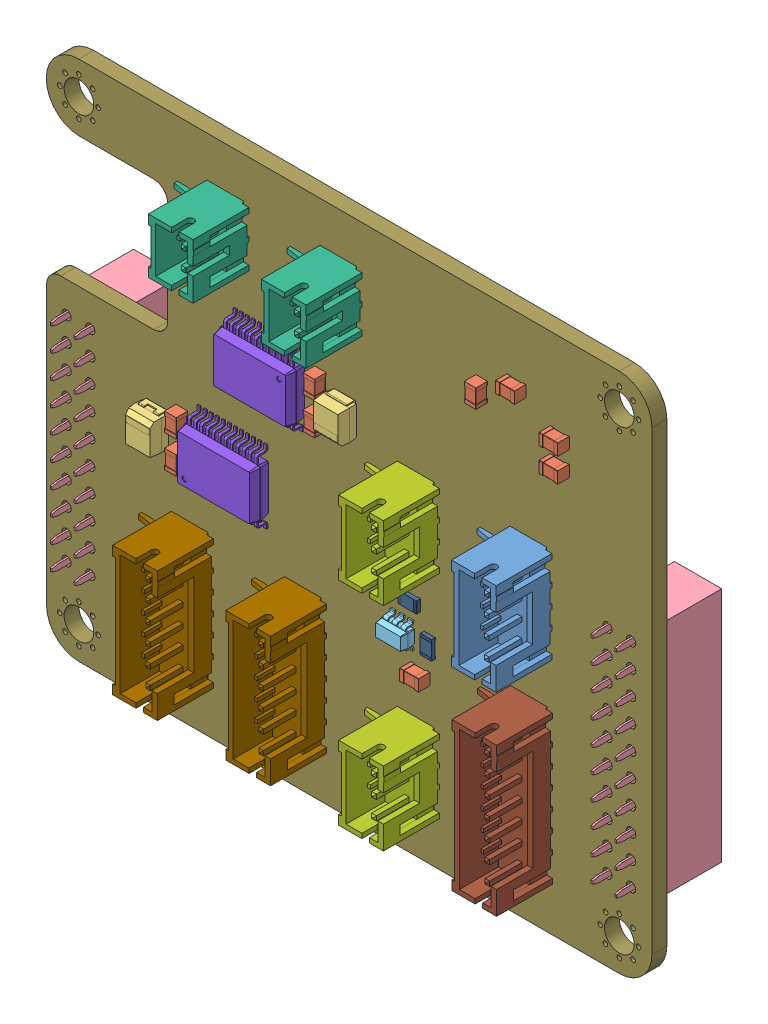
SolidWorks assembly seebum_peripherals, configuration Valor predeterminado. Lengths in mm.
Overall size (65 56 14.75).
54 component instances, 12 part files, 0 mates.
Components (placement in the parent):
- seebum_peripherals.step-1: seebum_peripherals.step [Valor predeterminado] at origin size (65 56 14.75)
  - JST_PH_S4B-PH-K_1x04_P2.00mm_Horizontal.step-1: JST_PH_S4B-PH-K_1x04_P2.00mm_Horizontal.step [Valor predeterminado] at (158.05 -87.4 1.65) x (0 -1 0) z (1 0 0) size (9.9 7.6 8.25)
    - JST_S4B_PH_K.step-1: JST_S4B_PH_K.step [Valor predeterminado] at origin size (9.9 7.6 8.25)
  - C_0805_2012Metric.step-1: C_0805_2012Metric.step [Valor predeterminado] at (122.875 -93 1.65) x (0 1 0) z (0 0 1) size (2 1.25 1.25)
    - C_0805_2012Metric-0.step-1: C_0805_2012Metric-0.step [Valor predeterminado] at origin size (2 1.25 1.25)
  - C_0805_2012Metric.step-2: C_0805_2012Metric.step [Valor predeterminado] at (158.8 -72 1.65) x (-1 0 0) z (0 0 1) size (2 1.25 1.25)
    - C_0805_2012Metric-0.step-1: C_0805_2012Metric-0.step [Valor predeterminado] at origin size (2 1.25 1.25)
  - CP_EIA-3528-21_Kemet-B.step-1: CP_EIA-3528-21_Kemet-B.step [Valor predeterminado] at (140.3917 -83.7275 1.65) x (0 1 0) z (0 0 1) size (3.5 2.8 2.1)
    - CP_EIA_3528_21_Kemet_B.step-1: CP_EIA_3528_21_Kemet_B.step [Valor predeterminado] at origin size (3.5 2.8 2.1)
  - PinSocket_2x10_P2.54mm_Vertical.step-1: PinSocket_2x10_P2.54mm_Vertical.step [Valor predeterminado] at (110.455 -89.64 0.15) x (-1 0 0) z (0 0 -1) size (5.08 25.4 10.1)
    - PinSocket_2x10_P254mm_Vertical.step-1: PinSocket_2x10_P254mm_Vertical.step [Valor predeterminado] at origin size (5.08 25.4 10.1)
  - SOT-23-5.step-1: SOT-23-5.step [Valor predeterminado] at (146.5625 -100.7 1.65) x (0 -1 0) z (0 0 1) size (2.8 2.9 1.55)
    - SOT_23_5.step-1: SOT_23_5.step [Valor predeterminado] at origin size (2.8 2.9 1.55)
  - CP_EIA-3528-21_Kemet-B.step-2: CP_EIA-3528-21_Kemet-B.step [Valor predeterminado] at (120.225 -94.7225 1.65) x (0 -1 0) z (0 0 1) size (3.5 2.8 2.1)
    - CP_EIA_3528_21_Kemet_B.step-1: CP_EIA_3528_21_Kemet_B.step [Valor predeterminado] at origin size (3.5 2.8 2.1)
  - C_0805_2012Metric.step-3: C_0805_2012Metric.step [Valor predeterminado] at (137.7417 -85.45 1.65) x (0 -1 0) z (0 0 1) size (2 1.25 1.25)
    - C_0805_2012Metric-0.step-1: C_0805_2012Metric-0.step [Valor predeterminado] at origin size (2 1.25 1.25)
  - JST_PH_S2B-PH-K_1x02_P2.00mm_Horizontal.step-1: JST_PH_S2B-PH-K_1x02_P2.00mm_Horizontal.step [Valor predeterminado] at (137.65 -71.5 1.65) x (0 -1 0) z (1 0 0) size (5.9 7.6 8.25)
    - JST_S2B_PH_K.step-1: JST_S2B_PH_K.step [Valor predeterminado] at origin size (5.9 7.6 8.25)
  - JST_PH_S3B-PH-K_1x03_P2.00mm_Horizontal.step-1: JST_PH_S3B-PH-K_1x03_P2.00mm_Horizontal.step [Valor predeterminado] at (145.95 -87.4 1.65) x (0 -1 0) z (1 0 0) size (7.9 7.6 8.25)
    - JST_S3B_PH_K.step-1: JST_S3B_PH_K.step [Valor predeterminado] at origin size (7.9 7.6 8.25)
  - C_0805_2012Metric.step-4: C_0805_2012Metric.step [Valor predeterminado] at (155.05 -74.15 1.65) x (0 1 0) z (0 0 1) size (2 1.25 1.25)
    - C_0805_2012Metric-0.step-1: C_0805_2012Metric-0.step [Valor predeterminado] at origin size (2 1.25 1.25)
  - JST_PH_S3B-PH-K_1x03_P2.00mm_Horizontal.step-2: JST_PH_S3B-PH-K_1x03_P2.00mm_Horizontal.step [Valor predeterminado] at (145.95 -110.2 1.65) x (0 -1 0) z (1 0 0) size (7.9 7.6 8.25)
    - JST_S3B_PH_K.step-1: JST_S3B_PH_K.step [Valor predeterminado] at origin size (7.9 7.6 8.25)
  - SSOP-24_5.3x8.2mm_P0.65mm.step-1: SSOP-24_5.3x8.2mm_P0.65mm.step [Valor predeterminado] at (128.375 -94.7 1.65) x (0 1 0) z (0 0 1) size (7.8 8.2 2.1)
    - SSOP_24_53x82mm_P065mm.step-1: SSOP_24_53x82mm_P065mm.step [Valor predeterminado] at origin size (7.8 8.2 2.1)
  - C_0805_2012Metric.step-5: C_0805_2012Metric.step [Valor predeterminado] at (163.45 -74.5 1.65) size (2 1.25 1.25)
    - C_0805_2012Metric-0.step-1: C_0805_2012Metric-0.step [Valor predeterminado] at origin size (2 1.25 1.25)
  - C_0805_2012Metric.step-6: C_0805_2012Metric.step [Valor predeterminado] at (137.7417 -82 1.65) x (0 -1 0) z (0 0 1) size (2 1.25 1.25)
    - C_0805_2012Metric-0.step-1: C_0805_2012Metric-0.step [Valor predeterminado] at origin size (2 1.25 1.25)
  - SSOP-24_5.3x8.2mm_P0.65mm.step-2: SSOP-24_5.3x8.2mm_P0.65mm.step [Valor predeterminado] at (132.2417 -83.75 1.65) x (0 -1 0) z (0 0 1) size (7.8 8.2 2.1)
    - SSOP_24_53x82mm_P065mm.step-1: SSOP_24_53x82mm_P065mm.step [Valor predeterminado] at origin size (7.8 8.2 2.1)
  - C_0805_2012Metric.step-7: C_0805_2012Metric.step [Valor predeterminado] at (163.45 -77.1 1.65) x (-1 0 0) z (0 0 1) size (2 1.25 1.25)
    - C_0805_2012Metric-0.step-1: C_0805_2012Metric-0.step [Valor predeterminado] at origin size (2 1.25 1.25)
  - JST_PH_S6B-PH-K_1x06_P2.00mm_Horizontal.step-1: JST_PH_S6B-PH-K_1x06_P2.00mm_Horizontal.step [Valor predeterminado] at (121.7 -104.2 1.65) x (0 -1 0) z (1 0 0) size (13.9 7.6 8.25)
    - JST_S6B_PH_K.step-1: JST_S6B_PH_K.step [Valor predeterminado] at origin size (13.9 7.6 8.25)
  - JST_PH_S6B-PH-K_1x06_P2.00mm_Horizontal.step-2: JST_PH_S6B-PH-K_1x06_P2.00mm_Horizontal.step [Valor predeterminado] at (133.8333 -104.2 1.65) x (0 -1 0) z (1 0 0) size (13.9 7.6 8.25)
    - JST_S6B_PH_K.step-1: JST_S6B_PH_K.step [Valor predeterminado] at origin size (13.9 7.6 8.25)
  - R_0805_2012Metric.step-1: R_0805_2012Metric.step [Valor predeterminado] at (149.5 -100.75 1.65) x (0 1 0) z (0 0 1) size (2 1.2 0.45)
    - R_0805_2012Metric-1.step-1: R_0805_2012Metric-1.step [Valor predeterminado] at origin size (2 1.2 0.45)
  - R_0805_2012Metric.step-2: R_0805_2012Metric.step [Valor predeterminado] at (147.5 -97.55 1.65) x (-1 0 0) z (0 0 1) size (2 1.2 0.45)
    - R_0805_2012Metric-1.step-1: R_0805_2012Metric-1.step [Valor predeterminado] at origin size (2 1.2 0.45)
  - JST_PH_S2B-PH-K_1x02_P2.00mm_Horizontal.step-2: JST_PH_S2B-PH-K_1x02_P2.00mm_Horizontal.step [Valor predeterminado] at (125.5167 -71.5 1.65) x (0 -1 0) z (1 0 0) size (5.9 7.6 8.25)
    - JST_S2B_PH_K.step-1: JST_S2B_PH_K.step [Valor predeterminado] at origin size (5.9 7.6 8.25)
  - PinSocket_2x10_P2.54mm_Vertical.step-2: PinSocket_2x10_P2.54mm_Vertical.step [Valor predeterminado] at (168.501 -89.64 0.15) x (-1 0 0) z (0 0 -1) size (5.08 25.4 10.1)
    - PinSocket_2x10_P254mm_Vertical.step-1: PinSocket_2x10_P254mm_Vertical.step [Valor predeterminado] at origin size (5.08 25.4 10.1)
  - C_0805_2012Metric.step-8: C_0805_2012Metric.step [Valor predeterminado] at (122.875 -96.45 1.65) x (0 1 0) z (0 0 1) size (2 1.25 1.25)
    - C_0805_2012Metric-0.step-1: C_0805_2012Metric-0.step [Valor predeterminado] at origin size (2 1.25 1.25)
  - C_0805_2012Metric.step-9: C_0805_2012Metric.step [Valor predeterminado] at (148.5 -103.9 1.65) size (2 1.25 1.25)
    - C_0805_2012Metric-0.step-1: C_0805_2012Metric-0.step [Valor predeterminado] at origin size (2 1.25 1.25)
  - JST_PH_S7B-PH-K_1x07_P2.00mm_Horizontal.step-1: JST_PH_S7B-PH-K_1x07_P2.00mm_Horizontal.step [Valor predeterminado] at (158.1 -102.2 1.65) x (0 -1 0) z (1 0 0) size (15.9 7.6 8.25)
    - JST_S7B_PH_K.step-1: JST_S7B_PH_K.step [Valor predeterminado] at origin size (15.9 7.6 8.25)
  - seebum_peripherals_PCB.step-1: seebum_peripherals_PCB.step [Valor predeterminado] at origin size (65 56 1.6)
